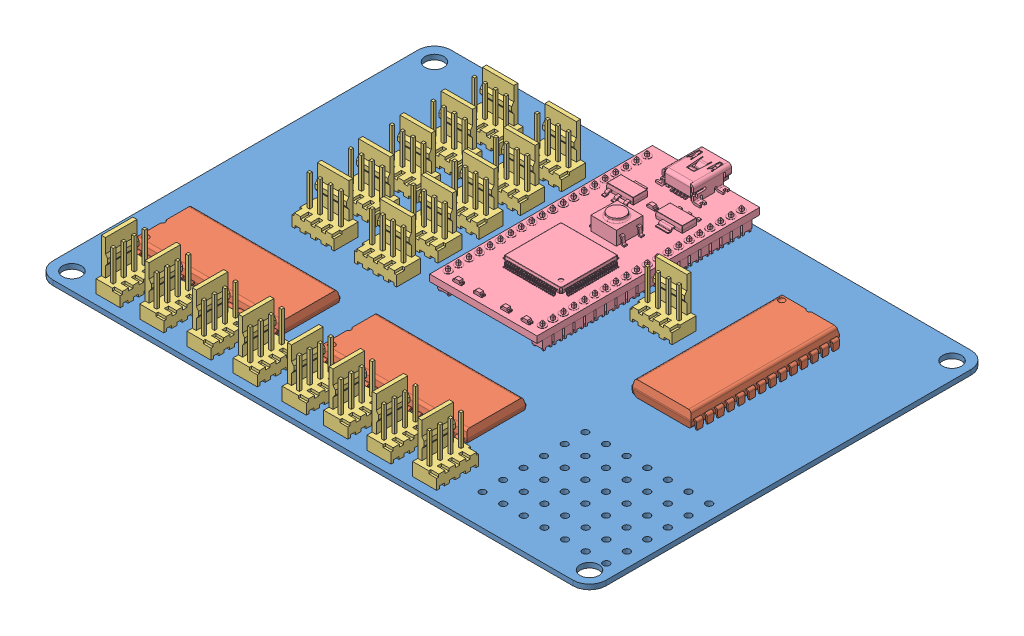
SolidWorks assembly electrobot, configuration Défaut. Lengths in mm.
Overall size (134.11 16.94 98.5).
24 component instances, 4 part files, 56 mates.
Components (placement in the parent):
- electrobot_pcb-1: electrobot_pcb [Défaut] at (-76.6981 6.946 -48.26) size (134.11 1.2 96.52)
- SW3DPS-DIP28-DEFAULT-1: SW3DPS-DIP28-DEFAULT [Défaut] at (-67.7352 6.166 32.8944) x (0.00089 0 -1) z (1 0 0.00089) size (15.62 7.94 36.01)
- SW3DPS-DIP28-DEFAULT-2: SW3DPS-DIP28-DEFAULT [Défaut] at (-22.6045 6.166 32.9345) x (0.00089 0 -1) z (1 0 0.00089) size (15.62 7.94 36.01)
- SW3DPS-DIP28-DEFAULT-4: SW3DPS-DIP28-DEFAULT [Défaut] at (21.5815 7.366 -31.9343) size (15.62 7.94 36.01)
- Molex-KK-4pins-1: Molex-KK-4pins [Défaut] at (-61.6362 9.7335 40.8711) x (0 0 -1) z (1 0 0) size (10.16 15.24 5.84)
- Molex-KK-4pins-2: Molex-KK-4pins [Défaut] at (-51.0648 9.7335 40.8711) x (0 0 -1) z (1 0 0) size (10.16 15.24 5.84)
- Molex-KK-4pins-4: Molex-KK-4pins [Défaut] at (-39.6069 9.7335 40.8711) x (0 0 -1) z (1 0 0) size (10.16 15.24 5.84)
- Molex-KK-4pins-5: Molex-KK-4pins [Défaut] at (-16.5239 9.7335 40.8711) x (0 0 -1) z (1 0 0) size (10.16 15.24 5.84)
- Molex-KK-4pins-6: Molex-KK-4pins [Défaut] at (-28.4179 9.7335 40.8711) x (0 0 -1) z (1 0 0) size (10.16 15.24 5.84)
- Molex-KK-4pins-7: Molex-KK-4pins [Défaut] at (15.0698 9.7335 40.8711) x (0 0 -1) z (1 0 0) size (10.16 15.24 5.84)
- Molex-KK-4pins-8: Molex-KK-4pins [Défaut] at (4.015 9.7335 40.8711) x (0 0 -1) z (1 0 0) size (10.16 15.24 5.84)
- Molex-KK-4pins-9: Molex-KK-4pins [Défaut] at (-6.4594 9.7335 40.8711) x (0 0 -1) z (1 0 0) size (10.16 15.24 5.84)
- MBED-1: MBED [Défaut] at (43.817 -0.358 39.2951) x (0 0 -1) z (0 1 0) size (55.78 26 11.64)
- Molex-KK-4pins-10: Molex-KK-4pins [Défaut] at (-34.595 9.7335 -24.8626) size (10.16 15.24 5.84)
- Molex-KK-4pins-11: Molex-KK-4pins [Défaut] at (-34.595 9.7335 -34.8626) size (10.16 15.24 5.84)
- Molex-KK-4pins-12: Molex-KK-4pins [Défaut] at (-34.595 9.7335 -4.8626) size (10.16 15.24 5.84)
- Molex-KK-4pins-13: Molex-KK-4pins [Défaut] at (-34.595 9.7335 -14.8626) size (10.16 15.24 5.84)
- Molex-KK-4pins-14: Molex-KK-4pins [Défaut] at (-34.595 9.7335 5.1374) size (10.16 15.24 5.84)
- Molex-KK-4pins-15: Molex-KK-4pins [Défaut] at (10.908 9.7335 -16.1402) size (10.16 15.24 5.84)
- Molex-KK-4pins-17: Molex-KK-4pins [Défaut] at (-49.755 9.7335 -34.8626) size (10.16 15.24 5.84)
- Molex-KK-4pins-18: Molex-KK-4pins [Défaut] at (-49.755 9.7335 -4.8626) size (10.16 15.24 5.84)
- Molex-KK-4pins-19: Molex-KK-4pins [Défaut] at (-49.755 9.7335 -14.8626) size (10.16 15.24 5.84)
- Molex-KK-4pins-20: Molex-KK-4pins [Défaut] at (-49.755 9.7335 -24.8626) size (10.16 15.24 5.84)
- Molex-KK-4pins-21: Molex-KK-4pins [Défaut] at (-49.755 9.7335 5.1374) size (10.16 15.24 5.84)
Mates (geometry in assembly coordinates):
- Parallèle1: parallel anti-aligned: plane of electrobot_pcb-1 through (-72.6981 8.146 -44.26) normal (0 1 0); plane of SW3DPS-DIP28-DEFAULT-1 through (-68.8804 6.946 31.4571) normal (0 -1 0)
- Parallèle4: parallel aligned: plane of electrobot_pcb-1 through (-72.6981 8.146 -44.26) normal (0 1 0); plane of SW3DPS-DIP28-DEFAULT-2 through (11.5532 10.826 31.5287) normal (0 1 0)
- Coïncidente4: coincident aligned: plane of electrobot_pcb-1 through (-72.6981 6.946 -44.26) normal (0 -1 0); plane of SW3DPS-DIP28-DEFAULT-2 through (-23.7496 6.946 31.4972) normal (0 -1 0)
- Coïncidente5: coincident aligned: plane of electrobot_pcb-1 through (-72.6981 6.946 -44.26) normal (0 -1 0); plane of SW3DPS-DIP28-DEFAULT-1 through (-68.8804 6.946 31.4571) normal (0 -1 0)
- Coïncidente6: coincident: plane of electrobot_pcb-1 through (-72.6981 8.146 -44.26) normal (0 1 0); line of Molex-KK-4pins-1 through (-58.6644 8.146 38.9661) axis (0 0 -1)
- Coïncidente7: coincident anti-aligned: plane of electrobot_pcb-1 through (-72.6981 8.146 -44.26) normal (0 1 0); plane of Molex-KK-4pins-1 through (-58.6644 8.146 41.5061) normal (0 -1 0)
- Parallèle5: parallel aligned: plane of electrobot_pcb-1 through (-72.6981 8.146 48.26) normal (0 0 1); plane of Molex-KK-4pins-1 through (-58.6644 8.146 45.9511) normal (0 0 1)
- Coïncidente10: coincident anti-aligned: plane of electrobot_pcb-1 through (-72.6981 8.146 -44.26) normal (0 1 0); plane of Molex-KK-4pins-2 through (-48.093 8.146 44.0461) normal (0 -1 0)
- Distance2: distance = 0 mm aligned: plane of Molex-KK-4pins-1 through (-58.6644 8.146 45.9511) normal (0 0 1); plane of Molex-KK-4pins-2 through (-48.093 8.146 45.9511) normal (0 0 1)
- Parallèle10: parallel aligned: plane of SW3DPS-DIP28-DEFAULT-1 through (-69.2348 9.076 32.4683) normal (-0.980195 0.198034 -0.000873); plane of SW3DPS-DIP28-DEFAULT-2 through (-24.1041 9.076 32.5085) normal (-0.980195 0.198034 -0.000873)
- Parallèle14: parallel aligned: plane of electrobot_pcb-1 through (-72.6981 8.146 48.26) normal (0 0 1); plane of SW3DPS-DIP28-DEFAULT-4 through (22.0915 9.896 2.5757) normal (0 0 1)
- Coïncidente15: coincident anti-aligned: plane of assembly through (-72.6981 8.146 -44.26) normal (0 1 0)
- Distance4: distance = 0 mm aligned: plane of SW3DPS-DIP28-DEFAULT-1 through (-35.5304 8.586 33.113) normal (-0.00089 0 1); plane of SW3DPS-DIP28-DEFAULT-2 through (-23.4196 8.586 33.1238) normal (-0.00089 0 1)
- Coïncidente17: coincident anti-aligned: plane of electrobot_pcb-1 through (-72.6981 8.146 -44.26) normal (0 1 0); plane of Molex-KK-4pins-4 through (-36.6351 8.146 44.0461) normal (0 -1 0)
- Parallèle16: parallel aligned: plane of Molex-KK-4pins-2 through (-48.093 8.146 45.9511) normal (0 0 1); plane of Molex-KK-4pins-4 through (-36.6351 8.146 45.9511) normal (0 0 1)
- Distance5: distance = 0 mm aligned: plane of Molex-KK-4pins-2 through (-48.093 8.146 45.9511) normal (0 0 1); plane of Molex-KK-4pins-4 through (-36.6351 8.146 45.9511) normal (0 0 1)
- Coïncidente18: coincident anti-aligned: plane of electrobot_pcb-1 through (-72.6981 8.146 -44.26) normal (0 1 0); plane of Molex-KK-4pins-5 through (-13.5521 8.146 44.0461) normal (0 -1 0)
- Distance7: distance = 0 mm aligned: plane of Molex-KK-4pins-4 through (-36.6351 8.146 45.9511) normal (0 0 1); plane of Molex-KK-4pins-5 through (-13.5521 8.146 45.9511) normal (0 0 1)
- Distance9: distance = 0 mm aligned: plane of Molex-KK-4pins-5 through (-13.5521 8.146 45.9511) normal (0 0 1); plane of Molex-KK-4pins-6 through (-25.4461 8.146 45.9511) normal (0 0 1)
- Coïncidente19: coincident anti-aligned: plane of electrobot_pcb-1 through (-72.6981 8.146 -44.26) normal (0 1 0); plane of Molex-KK-4pins-6 through (-25.4461 8.146 44.0461) normal (0 -1 0)
- Distance10: distance = 0 mm aligned: plane of Molex-KK-4pins-5 through (-13.5521 8.146 45.9511) normal (0 0 1); plane of Molex-KK-4pins-8 through (6.9868 8.146 45.9511) normal (0 0 1)
- Distance12: distance = 0 mm aligned: plane of Molex-KK-4pins-7 through (18.0416 8.146 45.9511) normal (0 0 1); plane of Molex-KK-4pins-9 through (-3.4876 8.146 45.9511) normal (0 0 1)
- Coïncidente20: coincident anti-aligned: plane of electrobot_pcb-1 through (-72.6981 8.146 -44.26) normal (0 1 0); plane of Molex-KK-4pins-7 through (18.0416 8.146 41.5061) normal (0 -1 0)
- Coïncidente21: coincident anti-aligned: plane of electrobot_pcb-1 through (-72.6981 8.146 -44.26) normal (0 1 0); plane of Molex-KK-4pins-8 through (6.9868 8.146 41.5061) normal (0 -1 0)
- Coïncidente22: coincident anti-aligned: plane of electrobot_pcb-1 through (-72.6981 8.146 -44.26) normal (0 1 0); plane of Molex-KK-4pins-9 through (-3.4876 8.146 41.5061) normal (0 -1 0)
- Distance13: distance = 0 mm aligned: plane of Molex-KK-4pins-8 through (6.9868 8.146 45.9511) normal (0 0 1); plane of Molex-KK-4pins-9 through (-3.4876 8.146 45.9511) normal (0 0 1)
- Coïncidente24: coincident aligned: plane of electrobot_pcb-1 through (-72.6981 8.146 -44.26) normal (0 1 0); plane of MBED-1 through (1.7355 8.146 3.7002) normal (0 1 0)
- Parallèle17: parallel anti-aligned: plane of electrobot_pcb-1 through (-72.6981 8.146 -48.26) normal (0 0 -1); plane of MBED-1 through (1.953 12.336 -48.4576) normal (0 0 1)
- Coïncidente25: coincident anti-aligned: plane of assembly through (-72.6981 8.146 -44.26) normal (0 1 0)
- Coïncidente26: coincident anti-aligned: plane of assembly through (-72.6981 8.146 -44.26) normal (0 1 0)
- Coïncidente27: coincident anti-aligned: plane of assembly through (-72.6981 8.146 -44.26) normal (0 1 0)
- Coïncidente28: coincident anti-aligned: plane of assembly through (-72.6981 8.146 -44.26) normal (0 1 0)
- Coïncidente29: coincident anti-aligned: plane of assembly through (-72.6981 8.146 -44.26) normal (0 1 0)
- Coïncidente30: coincident anti-aligned: plane of assembly through (-72.6981 8.146 -44.26) normal (0 1 0)
- Distance24: distance = 0 mm aligned: plane of Molex-KK-4pins-12; plane of Molex-KK-4pins-14
- Distance25: distance = 0 mm aligned: plane of Molex-KK-4pins-12; plane of Molex-KK-4pins-13
- Distance26: distance = 0 mm aligned: plane of Molex-KK-4pins-10; plane of Molex-KK-4pins-13
- Distance27: distance = 0 mm aligned: plane of Molex-KK-4pins-10; plane of Molex-KK-4pins-11
- Coïncidente45: coincident anti-aligned: plane of assembly through (-72.6981 8.146 -44.26) normal (0 1 0)
- Coïncidente46: coincident anti-aligned: plane of assembly through (-72.6981 8.146 -44.26) normal (0 1 0)
- Coïncidente48: coincident anti-aligned: plane of electrobot_pcb-1 through (-72.6981 8.146 -44.26) normal (0 1 0); plane of Molex-KK-4pins-20 through (-47.85 8.146 -21.8908) normal (0 -1 0)
- Distance28: distance = 0 mm aligned: plane of Molex-KK-4pins-14 through (-39.675 8.146 2.2672) normal (0 0 -1); plane of Molex-KK-4pins-21 through (-54.835 8.146 2.2672) normal (0 0 -1)
- Distance29: distance = 0 mm aligned: plane of Molex-KK-4pins-12 through (-39.675 8.146 -7.7328) normal (0 0 -1); plane of Molex-KK-4pins-18 through (-54.835 8.146 -7.7328) normal (0 0 -1)
- Distance30: distance = 0 mm aligned: plane of Molex-KK-4pins-13 through (-39.675 8.146 -17.7328) normal (0 0 -1); plane of Molex-KK-4pins-19 through (-54.835 8.146 -17.7328) normal (0 0 -1)
- Distance31: distance = 0 mm aligned: plane of Molex-KK-4pins-10 through (-39.675 8.146 -27.7328) normal (0 0 -1); plane of Molex-KK-4pins-20 through (-54.835 8.146 -27.7328) normal (0 0 -1)
- Distance32: distance = 0 mm aligned: plane of Molex-KK-4pins-11 through (-39.675 8.146 -37.7328) normal (0 0 -1); plane of Molex-KK-4pins-17 through (-54.835 8.146 -37.7328) normal (0 0 -1)
- Distance33: distance = 0 mm aligned: plane of Molex-KK-4pins-17; plane of Molex-KK-4pins-20
- Distance34: distance = 0 mm aligned: plane of Molex-KK-4pins-19; plane of Molex-KK-4pins-20
- Distance35: distance = -2000 mm aligned: plane of Molex-KK-4pins-18; plane of Molex-KK-4pins-19
- Distance36: distance = 0 mm aligned: plane of Molex-KK-4pins-18; plane of Molex-KK-4pins-21
- Coïncidente59: coincident anti-aligned: plane of assembly through (-72.6981 8.146 -44.26) normal (0 1 0)
- Distance37: distance = 10 mm: line of Molex-KK-4pins-18 through (-54.835 8.146 -7.7328) axis (0 1 0); line of Molex-KK-4pins-21 through (-54.835 8.146 2.2672) axis (0 1 0)
- Distance38: distance = 10 mm: line of Molex-KK-4pins-18 through (-54.835 8.146 -7.7328) axis (0 1 0); line of Molex-KK-4pins-19 through (-54.835 8.146 -17.7328) axis (0 1 0)
- Distance39: distance = 10 mm: line of Molex-KK-4pins-19 through (-54.835 8.146 -17.7328) axis (0 1 0); line of Molex-KK-4pins-20 through (-54.835 8.146 -27.7328) axis (0 1 0)
- Distance40: distance = 10 mm: line of Molex-KK-4pins-17 through (-54.835 8.146 -37.7328) axis (0 1 0); line of Molex-KK-4pins-20 through (-54.835 8.146 -27.7328) axis (0 1 0)
- Distance43: distance = 5 mm: line of Molex-KK-4pins-11 through (-39.675 8.146 -37.7328) axis (0 1 0); line of Molex-KK-4pins-17 through (-44.675 8.146 -37.7328) axis (0 1 0)
